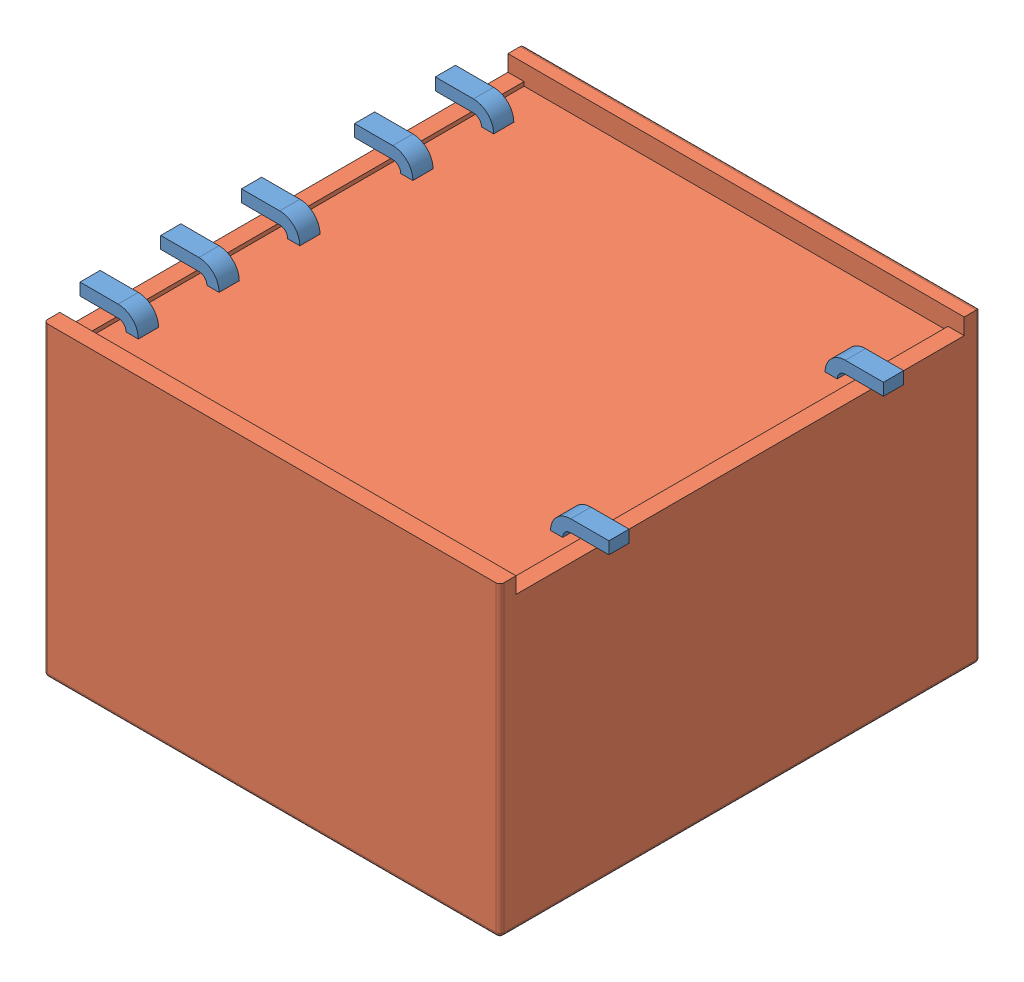
SolidWorks assembly TRS2, configuration Default. Lengths in mm.
Overall size (12.1 7.6 11.9).
8 component instances, 2 part files, 21 mates.
Components (placement in the parent):
- TRS2-Pin-1: TRS2-Pin [Default] at (-6.05 -0.15 -4.4) x (1 0 0) z (0 1 0) size (1.45 0.5 0.5)
- TRS2-Pin-2: TRS2-Pin [Default] at (-6.05 -0.15 -2.4) x (1 0 0) z (0 1 0) size (1.45 0.5 0.5)
- TRS2-Pin-3: TRS2-Pin [Default] at (-6.05 -0.15 0.4) x (1 0 0) z (0 1 0) size (1.45 0.5 0.5)
- TRS2-Pin-4: TRS2-Pin [Default] at (-6.05 -0.15 2.4) x (1 0 0) z (0 1 0) size (1.45 0.5 0.5)
- TRS2-Pin-5: TRS2-Pin [Default] at (-6.05 -0.15 4.4) x (1 0 0) z (0 1 0) size (1.45 0.5 0.5)
- TRS2-Pin-6: TRS2-Pin [Default] at (6.05 -0.15 3.4) x (-1 0 0) z (0 1 0) size (1.45 0.5 0.5)
- TRS2-Pin-7: TRS2-Pin [Default] at (6.05 -0.15 -3.4) x (-1 0 0) z (0 1 0) size (1.45 0.5 0.5)
- TRS2-Body-1: TRS2-Body [Default] x (0 0 1) z (1 0 0) size (11.9 7.6 11.3)
Mates (geometry in assembly coordinates):
- Coincident1: coincident: plane of TRS2-Pin-1 through (-6.05 0 -4.15) normal (0 1 0); plane of assembly through (0 0 0) normal (0 1 0)
- Distance1: distance = 4.4 mm: plane of TRS2-Pin-1 through (-6.05 -0.15 -4.4) normal (0 0 -1); plane of assembly through (0 0 0) normal (0 0 1)
- Distance2: distance = 4.605 mm: plane of TRS2-Pin-1 through (-4.605 -0.15 -4.4) normal (1 0 0); plane of assembly through (0 0 0) normal (1 0 0)
- Coincident4: coincident: plane of TRS2-Pin-2 through (-6.05 0 -2.15) normal (0 1 0); plane of assembly through (0 0 0) normal (0 1 0)
- Coincident5: coincident: plane of TRS2-Pin-1 through (-4.605 -0.15 -3.9) normal (1 0 0); plane of TRS2-Pin-2 through (-4.605 -0.15 -1.9) normal (1 0 0)
- Distance3: distance = 2 mm: plane of TRS2-Pin-2 through (-6.05 -0.15 -2.4) normal (0 0 -1); plane of TRS2-Pin-1 through (-6.05 -0.15 -4.4) normal (0 0 -1)
- Coincident7: coincident: plane of TRS2-Pin-3 through (-6.05 0 0.65) normal (0 1 0); plane of assembly through (0 0 0) normal (0 1 0)
- Coincident8: coincident: plane of TRS2-Pin-1 through (-4.605 -0.15 -3.9) normal (1 0 0); plane of TRS2-Pin-3 through (-4.605 -0.15 0.9) normal (1 0 0)
- Distance4: distance = 2.8 mm: plane of TRS2-Pin-3 through (-6.05 -0.15 0.4) normal (0 0 -1); plane of TRS2-Pin-2 through (-6.05 -0.15 -2.4) normal (0 0 -1)
- Coincident10: coincident: plane of TRS2-Pin-4 through (-6.05 0 2.65) normal (0 1 0); plane of assembly through (0 0 0) normal (0 1 0)
- Coincident11: coincident: plane of TRS2-Pin-1 through (-4.605 -0.15 -3.9) normal (1 0 0); plane of TRS2-Pin-4 through (-4.605 -0.15 2.9) normal (1 0 0)
- Distance5: distance = 2 mm: plane of TRS2-Pin-4 through (-6.05 -0.15 2.4) normal (0 0 -1); plane of TRS2-Pin-3 through (-6.05 -0.15 0.4) normal (0 0 -1)
- Coincident13: coincident: plane of TRS2-Pin-5 through (-6.05 0 4.65) normal (0 1 0); plane of assembly through (0 0 0) normal (0 1 0)
- Coincident14: coincident: plane of TRS2-Pin-1 through (-4.605 -0.15 -3.9) normal (1 0 0); plane of TRS2-Pin-5 through (-4.605 -0.15 4.9) normal (1 0 0)
- Distance6: distance = 2 mm: plane of TRS2-Pin-5 through (-6.05 -0.15 4.4) normal (0 0 -1); plane of TRS2-Pin-4 through (-6.05 -0.15 2.4) normal (0 0 -1)
- Coincident16: coincident: plane of TRS2-Pin-6 through (6.05 0 3.65) normal (0 1 0); plane of assembly through (0 0 0) normal (0 1 0)
- Distance7: distance = 4.605 mm: plane of TRS2-Pin-6 through (4.605 -0.15 3.4) normal (-1 0 0); plane of assembly through (0 0 0) normal (1 0 0)
- Distance8: distance = 3.4 mm: plane of TRS2-Pin-6 through (6.05 -0.15 3.4) normal (0 0 1); plane of assembly through (0 0 0) normal (0 0 1)
- Coincident19: coincident: plane of TRS2-Pin-1 through (-4.605 -0.5 -4.15) normal (0 -1 0); plane of TRS2-Body-1 through (0 -0.5 0) normal (0 1 0)
- Coincident20: coincident: plane of TRS2-Body-1 through (0 0 0) normal (0 0 1); plane of assembly
- Coincident21: coincident: plane of TRS2-Body-1 through (0 0 0) normal (1 0 0); plane of assembly
